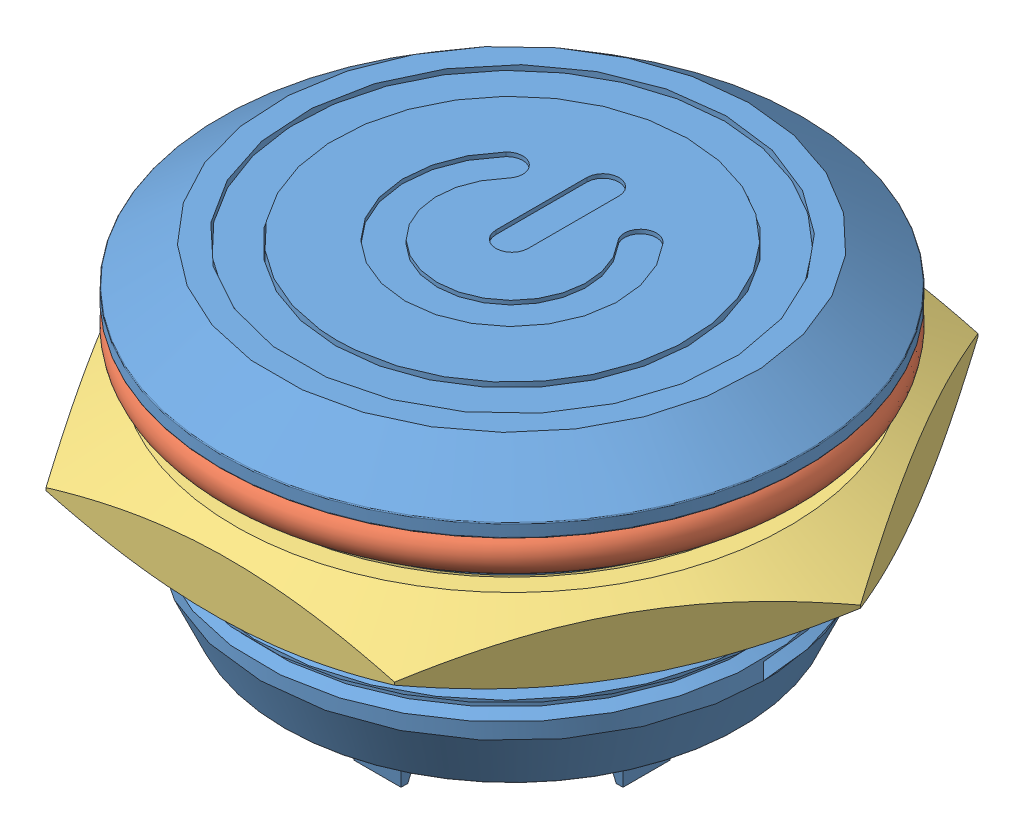
SolidWorks assembly Btn19PWR-LED, configuration По умолчанию. Lengths in mm.
Overall size (26.01 14.8 25.87).
3 component instances, 3 part files, 3 mates.
Components (placement in the parent):
- Btn19PWR-LED-1: Btn19PWR-LED [По умолчанию] at (-88.8816 23.1261 62.0599) size (21.8 14.8 21.8)
- O-ring rubber19-1: O-ring rubber19 [По умолчанию] at (-88.8816 31.4866 62.0599) x (-0.978034 0 0.208444) z (-0.208444 0 -0.978034) size (21.8 1.49 21.8)
- Nut19-1: Nut19 [По умолчанию] at (-88.8816 28.626 62.0599) x (0.016898 0 0.999857) z (-0.999857 0 0.016898) size (22.2 3.82 25.63)
Mates (geometry in assembly coordinates):
- Совпадение3: coincident: plane of Btn19PWR-LED-1 through (-78.0316 32.2261 62.0599) normal (0 -1 0); plane of O-ring rubber19-1 through (-98.6864 32.2261 64.1495) normal (0 1 0)
- Концентричный1: concentric: circle of Btn19PWR-LED-1; cylinder of O-ring rubber19-1 through (-88.8816 31.4866 62.0599) axis (0 -1 0) radius 9.4105
- Винт1: screw = 0.7 mm: circle of Nut19-1; cylinder of Btn19PWR-LED-1 through (-88.8816 23.1261 62.0599) axis (0 -1 0) radius 9.4
